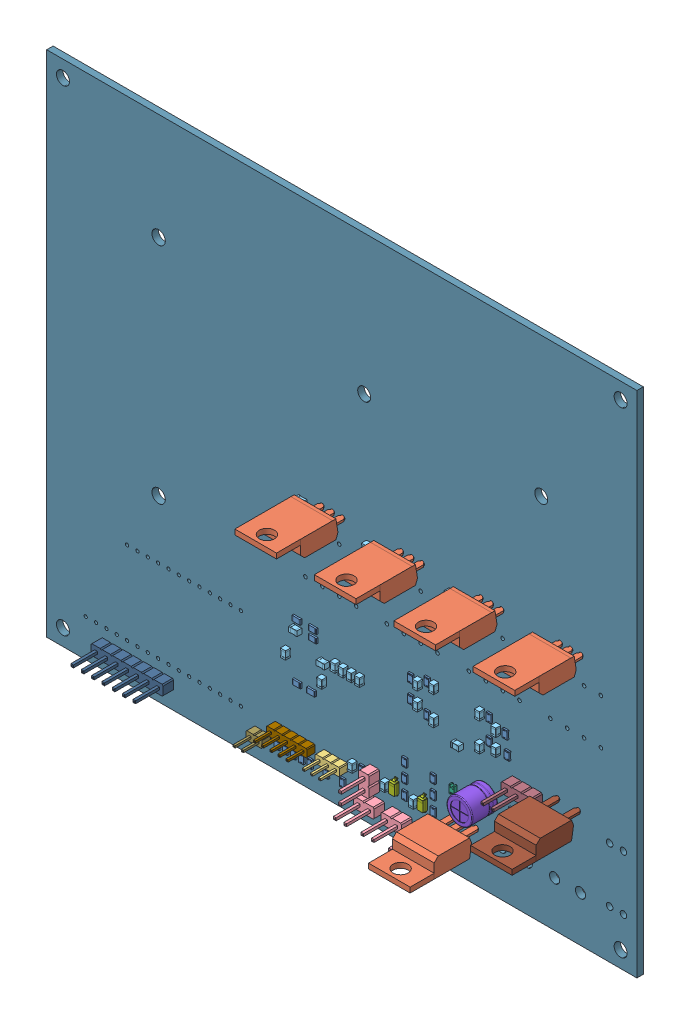
SolidWorks assembly Board, configuration Default. Lengths in mm.
Overall size (145 125 28.53).
161 component instances, 14 part files, 0 mates.
Components (placement in the parent):
- R_0805_2012Metric-1: R_0805_2012Metric [Default] at (177.75 -104.1625 1.63) x (0 1 0) z (0 0 1) size (2 1.2 0.45)
  - SOLID-1: SOLID [Default] at origin size (2 1.2 0.45)
- R_0805_2012Metric-2: R_0805_2012Metric [Default] at (182.25 -109.9125 1.63) x (0 1 0) z (0 0 1) size (2 1.2 0.45)
  - SOLID-1: SOLID [Default] at origin size (2 1.2 0.45)
- R_0805_2012Metric-3: R_0805_2012Metric [Default] at (146.4625 -130.9125 1.63) x (0 1 0) z (0 0 1) size (2 1.2 0.45)
  - SOLID-1: SOLID [Default] at origin size (2 1.2 0.45)
- TO-220-3_Vertical-1: TO-220-3_Vertical [Default] at (194.92 -79.89 1.63) size (10.25 4.46 28.53)
  - SOLID_2-1: SOLID_2 [Default] at origin size (10.25 4.46 28.53)
- R_0805_2012Metric-4: R_0805_2012Metric [Default] at (177.75 -109.25 1.63) x (0 1 0) z (0 0 1) size (2 1.2 0.45)
  - SOLID-1: SOLID [Default] at origin size (2 1.2 0.45)
- R_0805_2012Metric-5: R_0805_2012Metric [Default] at (164 -124 1.63) x (0 1 0) z (0 0 1) size (2 1.2 0.45)
  - SOLID-1: SOLID [Default] at origin size (2 1.2 0.45)
- PinHeader_1x03_P2.00mm_Vertical-1: PinHeader_1x03_P2.00mm_Vertical [Default] at (137.75 -132.5 1.63) x (0 1 0) z (0 0 1) size (2 6 8.8)
  - SOLID_3-1: SOLID_3 [Default] at origin size (2 6 8.8)
- PinHeader_1x02_P2.54mm_Vertical-1: PinHeader_1x02_P2.54mm_Vertical [Default] at (149.25 -132.775 1.63) x (-1 0 0) z (0 0 1) size (2.54 5.08 11.54)
  - SOLID_4-1: SOLID_4 [Default] at origin size (2.54 5.08 11.54)
- PinHeader_1x02_P2.54mm_Vertical-2: PinHeader_1x02_P2.54mm_Vertical [Default] at (161.5 -136.475 1.63) x (0 1 0) z (0 0 1) size (2.54 5.08 11.54)
  - SOLID_4-1: SOLID_4 [Default] at origin size (2.54 5.08 11.54)
- C_0805_2012Metric-1: C_0805_2012Metric [Default] at (152.5 -131 1.63) x (0 -1 0) z (0 0 1) size (2 1.25 1.25)
  - SOLID_5-1: SOLID_5 [Default] at origin size (2 1.25 1.25)
- TO-220-3_Vertical-2: TO-220-3_Vertical [Default] at (155.92 -79.89 1.63) size (10.25 4.46 28.53)
  - SOLID_2-1: SOLID_2 [Default] at origin size (10.25 4.46 28.53)
- D_0805_2012Metric-1: D_0805_2012Metric [Default] at (187.25 -121.2267 1.63) x (-1 0 0) z (0 0 1) size (2 1.27 0.8)
  - SOLID_6-1: SOLID_6 [Default] at origin size (2 1.27 0.8)
- R_0805_2012Metric-6: R_0805_2012Metric [Default] at (150 -82.75 1.63) x (0 1 0) z (0 0 1) size (2 1.2 0.45)
  - SOLID-1: SOLID [Default] at origin size (2 1.2 0.45)
- D_SOD-123-1: D_SOD-123 [Default] at (154.75 -130.4 1.63) x (0 -1 0) z (0 0 1) size (3.8 1.6 1.25)
  - SOLID_7-1: SOLID_7 [Default] at origin size (3.8 1.6 1.25)
- R_0805_2012Metric-7: R_0805_2012Metric [Default] at (131.75 -83.25 1.63) size (2 1.2 0.45)
  - SOLID-1: SOLID [Default] at origin size (2 1.2 0.45)
- R_0805_2012Metric-8: R_0805_2012Metric [Default] at (183.6625 -123.2392 1.63) x (-1 0 0) z (0 0 1) size (2 1.2 0.45)
  - SOLID-1: SOLID [Default] at origin size (2 1.2 0.45)
- C_0805_2012Metric-2: C_0805_2012Metric [Default] at (168.25 -82.75 1.63) x (0 -1 0) z (0 0 1) size (2 1.25 1.25)
  - SOLID_5-1: SOLID_5 [Default] at origin size (2 1.25 1.25)
- R_0805_2012Metric-9: R_0805_2012Metric [Default] at (133.75 -135.9125 1.63) x (0 1 0) z (0 0 1) size (2 1.2 0.45)
  - SOLID-1: SOLID [Default] at origin size (2 1.2 0.45)
- C_0805_2012Metric-3: C_0805_2012Metric [Default] at (144.25 -111.75 1.63) x (0 -1 0) z (0 0 1) size (2 1.25 1.25)
  - SOLID_5-1: SOLID_5 [Default] at origin size (2 1.25 1.25)
- R_0805_2012Metric-10: R_0805_2012Metric [Default] at (129.75 -135.9125 1.63) x (0 1 0) z (0 0 1) size (2 1.2 0.45)
  - SOLID-1: SOLID [Default] at origin size (2 1.2 0.45)
- R_0805_2012Metric-11: R_0805_2012Metric [Default] at (131.75 -135.9125 1.63) x (0 1 0) z (0 0 1) size (2 1.2 0.45)
  - SOLID-1: SOLID [Default] at origin size (2 1.2 0.45)
- C_0805_2012Metric-4: C_0805_2012Metric [Default] at (170.05 -126.5 1.63) size (2 1.25 1.25)
  - SOLID_5-1: SOLID_5 [Default] at origin size (2 1.25 1.25)
- R_0805_2012Metric-12: R_0805_2012Metric [Default] at (134.0875 -120.5187 1.63) size (2 1.2 0.45)
  - SOLID-1: SOLID [Default] at origin size (2 1.2 0.45)
- C_0805_2012Metric-5: C_0805_2012Metric [Default] at (179.75 -105.6625 1.63) x (0 1 0) z (0 0 1) size (2 1.25 1.25)
  - SOLID_5-1: SOLID_5 [Default] at origin size (2 1.25 1.25)
- C_0805_2012Metric-6: C_0805_2012Metric [Default] at (170.25 -113.6625 1.63) size (2 1.25 1.25)
  - SOLID_5-1: SOLID_5 [Default] at origin size (2 1.25 1.25)
- C_0805_2012Metric-7: C_0805_2012Metric [Default] at (137.25 -112.75 1.63) x (-1 0 0) z (0 0 1) size (2 1.25 1.25)
  - SOLID_5-1: SOLID_5 [Default] at origin size (2 1.25 1.25)
- C_0805_2012Metric-8: C_0805_2012Metric [Default] at (188.25 -82.75 1.63) x (0 -1 0) z (0 0 1) size (2 1.25 1.25)
  - SOLID_5-1: SOLID_5 [Default] at origin size (2 1.25 1.25)
- R_0805_2012Metric-13: R_0805_2012Metric [Default] at (164 -127.5 1.63) x (0 1 0) z (0 0 1) size (2 1.2 0.45)
  - SOLID-1: SOLID [Default] at origin size (2 1.2 0.45)
- R_0805_2012Metric-14: R_0805_2012Metric [Default] at (190.25 -82.75 1.63) x (0 1 0) z (0 0 1) size (2 1.2 0.45)
  - SOLID-1: SOLID [Default] at origin size (2 1.2 0.45)
- CP_Radial_D6.3mm_P2.50mm-1: CP_Radial_D6.3mm_P2.50mm [Default] at (175.25 -121.75 1.63) size (7.79 8.05 8.3)
  - SOLID_8-1: SOLID_8 [Default] at origin size (7.79 8.05 8.3)
- R_0805_2012Metric-15: R_0805_2012Metric [Default] at (157 -127.5 1.63) x (0 1 0) z (0 0 1) size (2 1.2 0.45)
  - SOLID-1: SOLID [Default] at origin size (2 1.2 0.45)
- PinHeader_1x02_P2.54mm_Vertical-3: PinHeader_1x02_P2.54mm_Vertical [Default] at (168.21 -136.5 1.63) x (0 1 0) z (0 0 1) size (2.54 5.08 11.54)
  - SOLID_4-1: SOLID_4 [Default] at origin size (2.54 5.08 11.54)
- R_0805_2012Metric-16: R_0805_2012Metric [Default] at (134.5 -109.0187 1.63) size (2 1.2 0.45)
  - SOLID-1: SOLID [Default] at origin size (2 1.2 0.45)
- PinHeader_1x02_P2.54mm_Vertical-4: PinHeader_1x02_P2.54mm_Vertical [Default] at (147.98 -136.5 1.63) x (0 1 0) z (0 0 1) size (2.54 5.08 11.54)
  - SOLID_4-1: SOLID_4 [Default] at origin size (2.54 5.08 11.54)
- R_0805_2012Metric-17: R_0805_2012Metric [Default] at (181.75 -105.6625 1.63) x (0 -1 0) z (0 0 1) size (2 1.2 0.45)
  - SOLID-1: SOLID [Default] at origin size (2 1.2 0.45)
- PinHeader_1x05_P2.00mm_Vertical-1: PinHeader_1x05_P2.00mm_Vertical [Default] at (125.75 -132.5 1.63) x (0 1 0) z (0 0 1) size (2 10 8.8)
  - SOLID_9-1: SOLID_9 [Default] at origin size (2 10 8.8)
- C_0805_2012Metric-9: C_0805_2012Metric [Default] at (174 -126.5 1.63) x (-1 0 0) z (0 0 1) size (2 1.25 1.25)
  - SOLID_5-1: SOLID_5 [Default] at origin size (2 1.25 1.25)
- C_0805_2012Metric-10: C_0805_2012Metric [Default] at (160.5 -105.4125 1.63) x (0 1 0) z (0 0 1) size (2 1.25 1.25)
  - SOLID_5-1: SOLID_5 [Default] at origin size (2 1.25 1.25)
- R_0805_2012Metric-18: R_0805_2012Metric [Default] at (162.5 -104.1625 1.63) x (0 1 0) z (0 0 1) size (2 1.2 0.45)
  - SOLID-1: SOLID [Default] at origin size (2 1.2 0.45)
- R_0805_2012Metric-19: R_0805_2012Metric [Default] at (164 -131.0875 1.63) x (0 1 0) z (0 0 1) size (2 1.2 0.45)
  - SOLID-1: SOLID [Default] at origin size (2 1.2 0.45)
- R_0805_2012Metric-20: R_0805_2012Metric [Default] at (127.75 -135.9125 1.63) x (0 1 0) z (0 0 1) size (2 1.2 0.45)
  - SOLID-1: SOLID [Default] at origin size (2 1.2 0.45)
- C_0805_2012Metric-11: C_0805_2012Metric [Default] at (131.75 -81 1.63) x (-1 0 0) z (0 0 1) size (2 1.25 1.25)
  - SOLID_5-1: SOLID_5 [Default] at origin size (2 1.25 1.25)
- PinHeader_1x02_P2.54mm_Vertical-5: PinHeader_1x02_P2.54mm_Vertical [Default] at (154.725 -136.5 1.63) x (0 1 0) z (0 0 1) size (2.54 5.08 11.54)
  - SOLID_4-1: SOLID_4 [Default] at origin size (2.54 5.08 11.54)
- TO-220-3_Vertical-3: TO-220-3_Vertical [Default] at (175.46 -79.945 1.63) size (10.25 4.46 28.53)
  - SOLID_2-1: SOLID_2 [Default] at origin size (10.25 4.46 28.53)
- C_0805_2012Metric-12: C_0805_2012Metric [Default] at (159.5 -131.05 1.63) x (0 -1 0) z (0 0 1) size (2 1.25 1.25)
  - SOLID_5-1: SOLID_5 [Default] at origin size (2 1.25 1.25)
- R_0805_2012Metric-21: R_0805_2012Metric [Default] at (183.6625 -121.2392 1.63) x (-1 0 0) z (0 0 1) size (2 1.2 0.45)
  - SOLID-1: SOLID [Default] at origin size (2 1.2 0.45)
- R_0805_2012Metric-22: R_0805_2012Metric [Default] at (134.5 -107.0187 1.63) x (-1 0 0) z (0 0 1) size (2 1.2 0.45)
  - SOLID-1: SOLID [Default] at origin size (2 1.2 0.45)
- C_0805_2012Metric-13: C_0805_2012Metric [Default] at (142.25 -111.75 1.63) x (0 -1 0) z (0 0 1) size (2 1.25 1.25)
  - SOLID_5-1: SOLID_5 [Default] at origin size (2 1.25 1.25)
- C_0805_2012Metric-14: C_0805_2012Metric [Default] at (164.5 -111.2 1.63) x (0 -1 0) z (0 0 1) size (2 1.25 1.25)
  - SOLID_5-1: SOLID_5 [Default] at origin size (2 1.25 1.25)
- C_0805_2012Metric-15: C_0805_2012Metric [Default] at (175.75 -104.1625 1.63) x (0 1 0) z (0 0 1) size (2 1.25 1.25)
  - SOLID_5-1: SOLID_5 [Default] at origin size (2 1.25 1.25)
- R_0805_2012Metric-23: R_0805_2012Metric [Default] at (158.5 -105.4125 1.63) x (0 -1 0) z (0 0 1) size (2 1.2 0.45)
  - SOLID-1: SOLID [Default] at origin size (2 1.2 0.45)
- C_0805_2012Metric-16: C_0805_2012Metric [Default] at (128.0875 -115.0187 1.63) x (0 1 0) z (0 0 1) size (2 1.25 1.25)
  - SOLID_5-1: SOLID_5 [Default] at origin size (2 1.25 1.25)
- TO-220-3_Vertical-4: TO-220-3_Vertical [Default] at (174.29 -129.555 1.63) x (-1 0 0) z (0 0 1) size (10.25 4.46 28.53)
  - SOLID_2-1: SOLID_2 [Default] at origin size (10.25 4.46 28.53)
- R_0805_2012Metric-24: R_0805_2012Metric [Default] at (137.75 -136 1.63) x (0 1 0) z (0 0 1) size (2 1.2 0.45)
  - SOLID-1: SOLID [Default] at origin size (2 1.2 0.45)
- R_0805_2012Metric-25: R_0805_2012Metric [Default] at (130.5875 -120.5187 1.63) size (2 1.2 0.45)
  - SOLID-1: SOLID [Default] at origin size (2 1.2 0.45)
- R_0805_2012Metric-26: R_0805_2012Metric [Default] at (170.25 -82.75 1.63) x (0 1 0) z (0 0 1) size (2 1.2 0.45)
  - SOLID-1: SOLID [Default] at origin size (2 1.2 0.45)
- PinHeader_1x07_P2.54mm_Vertical-1: PinHeader_1x07_P2.54mm_Vertical [Default] at (98.7 -136.25 1.63) x (0 -1 0) z (0 0 1) size (2.54 17.78 11.54)
  - SOLID_10-1: SOLID_10 [Default] at origin size (2.54 17.78 11.54)
- R_0805_2012Metric-27: R_0805_2012Metric [Default] at (157 -124 1.63) x (0 1 0) z (0 0 1) size (2 1.2 0.45)
  - SOLID-1: SOLID [Default] at origin size (2 1.2 0.45)
- TO-220-2_Vertical-1: TO-220-2_Vertical [Default] at (199.34 -113.255 1.63) x (-1 0 0) z (0 0 1) size (10.25 4.46 28.53)
  - SOLID_11-1: SOLID_11 [Default] at origin size (10.25 4.46 28.53)
- R_0805_2012Metric-28: R_0805_2012Metric [Default] at (157 -131.0875 1.63) x (0 1 0) z (0 0 1) size (2 1.2 0.45)
  - SOLID-1: SOLID [Default] at origin size (2 1.2 0.45)
- PinHeader_1x02_P2.00mm_Vertical-1: PinHeader_1x02_P2.00mm_Vertical [Default] at (120.75 -136 1.63) x (0 1 0) z (0 0 1) size (2 4 8.8)
  - SOLID_12-1: SOLID_12 [Default] at origin size (2 4 8.8)
- R_0805_2012Metric-29: R_0805_2012Metric [Default] at (130.5 -107.0187 1.63) size (2 1.2 0.45)
  - SOLID-1: SOLID [Default] at origin size (2 1.2 0.45)
- C_0805_2012Metric-17: C_0805_2012Metric [Default] at (179.75 -109.9125 1.63) x (0 -1 0) z (0 0 1) size (2 1.25 1.25)
  - SOLID_5-1: SOLID_5 [Default] at origin size (2 1.25 1.25)
- C_0805_2012Metric-18: C_0805_2012Metric [Default] at (160.5 -109.8625 1.63) x (0 -1 0) z (0 0 1) size (2 1.25 1.25)
  - SOLID_5-1: SOLID_5 [Default] at origin size (2 1.25 1.25)
- C_0805_2012Metric-19: C_0805_2012Metric [Default] at (144.4625 -130.9125 1.63) x (0 1 0) z (0 0 1) size (2 1.25 1.25)
  - SOLID_5-1: SOLID_5 [Default] at origin size (2 1.25 1.25)
- C_0805_2012Metric-20: C_0805_2012Metric [Default] at (164.5 -104.1625 1.63) x (0 1 0) z (0 0 1) size (2 1.25 1.25)
  - SOLID_5-1: SOLID_5 [Default] at origin size (2 1.25 1.25)
- R_0805_2012Metric-30: R_0805_2012Metric [Default] at (158.5 -109.9125 1.63) x (0 1 0) z (0 0 1) size (2 1.2 0.45)
  - SOLID-1: SOLID [Default] at origin size (2 1.2 0.45)
- C_0805_2012Metric-21: C_0805_2012Metric [Default] at (148 -82.75 1.63) x (0 -1 0) z (0 0 1) size (2 1.25 1.25)
  - SOLID_5-1: SOLID_5 [Default] at origin size (2 1.25 1.25)
- C_0805_2012Metric-22: C_0805_2012Metric [Default] at (146.25 -111.75 1.63) x (0 -1 0) z (0 0 1) size (2 1.25 1.25)
  - SOLID_5-1: SOLID_5 [Default] at origin size (2 1.25 1.25)
- D_SOD-123-2: D_SOD-123 [Default] at (161.75 -130.35 1.63) x (0 -1 0) z (0 0 1) size (3.8 1.6 1.25)
  - SOLID_7-1: SOLID_7 [Default] at origin size (3.8 1.6 1.25)
- C_0805_2012Metric-23: C_0805_2012Metric [Default] at (137 -116.75 1.63) x (0 1 0) z (0 0 1) size (2 1.25 1.25)
  - SOLID_5-1: SOLID_5 [Default] at origin size (2 1.25 1.25)
- R_0805_2012Metric-31: R_0805_2012Metric [Default] at (125.75 -135.9125 1.63) x (0 1 0) z (0 0 1) size (2 1.2 0.45)
  - SOLID-1: SOLID [Default] at origin size (2 1.2 0.45)
- C_0805_2012Metric-24: C_0805_2012Metric [Default] at (175.75 -111.1625 1.63) x (0 -1 0) z (0 0 1) size (2 1.25 1.25)
  - SOLID_5-1: SOLID_5 [Default] at origin size (2 1.25 1.25)
- C_0805_2012Metric-25: C_0805_2012Metric [Default] at (140.25 -111.75 1.63) x (0 -1 0) z (0 0 1) size (2 1.25 1.25)
  - SOLID_5-1: SOLID_5 [Default] at origin size (2 1.25 1.25)
- TO-220-3_Vertical-5: TO-220-3_Vertical [Default] at (136.38 -79.945 1.63) size (10.25 4.46 28.53)
  - SOLID_2-1: SOLID_2 [Default] at origin size (10.25 4.46 28.53)
- D_0805_2012Metric-2: D_0805_2012Metric [Default] at (169 -123.75 1.63) x (0 -1 0) z (0 0 1) size (2 1.27 0.8)
  - SOLID_6-1: SOLID_6 [Default] at origin size (2 1.27 0.8)
- R_0805_2012Metric-32: R_0805_2012Metric [Default] at (141.75 -136 1.63) x (0 1 0) z (0 0 1) size (2 1.2 0.45)
  - SOLID-1: SOLID [Default] at origin size (2 1.2 0.45)
- R_0805_2012Metric-33: R_0805_2012Metric [Default] at (162.5 -111.25 1.63) x (0 -1 0) z (0 0 1) size (2 1.2 0.45)
  - SOLID-1: SOLID [Default] at origin size (2 1.2 0.45)
- PinHeader_1x03_P2.54mm_Vertical-1: PinHeader_1x03_P2.54mm_Vertical [Default] at (184.21 -115.235 1.63) x (0 1 0) z (0 0 1) size (2.54 7.62 11.54)
  - SOLID_13-1: SOLID_13 [Default] at origin size (2.54 7.62 11.54)
- C_0805_2012Metric-26: C_0805_2012Metric [Default] at (130.5 -109.0187 1.63) x (-1 0 0) z (0 0 1) size (2 1.25 1.25)
  - SOLID_5-1: SOLID_5 [Default] at origin size (2 1.25 1.25)
- Main PCB-1: Main PCB [Default] at origin size (145 125 1.58)
